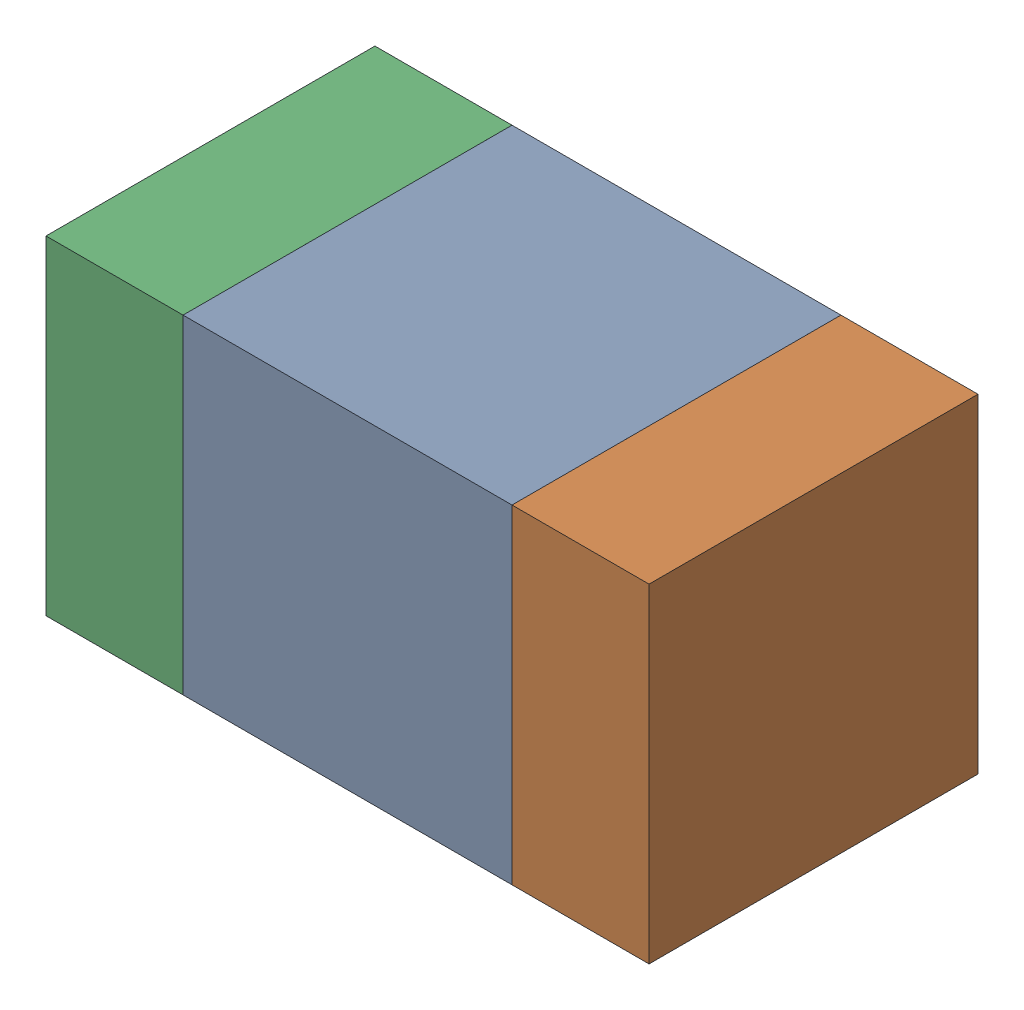
SolidWorks assembly C315_1PCB, configuration Default. Lengths in mm.
Overall size (1.1 0.6 0.6).
6 component instances, 2 part files, 0 mates.
Components (placement in the parent):
- 761606048-1: 761606048 [Default] at (129.6 113.5 -2.2638) size (0.6 0.6 0.6)
  - Extruded_9-1: Extruded_9 [Default] at origin size (0.6 0.6 0.6)
- 854785160-1: 854785160 [Default] at (130.025 113.5 -2.2638) size (0.25 0.6 0.6)
  - Extruded_19-1: Extruded_19 [Default] at origin size (0.25 0.6 0.6)
- 854785160-2: 854785160 [Default] at (129.175 113.5 -2.2638) size (0.25 0.6 0.6)
  - Extruded_19-1: Extruded_19 [Default] at origin size (0.25 0.6 0.6)
